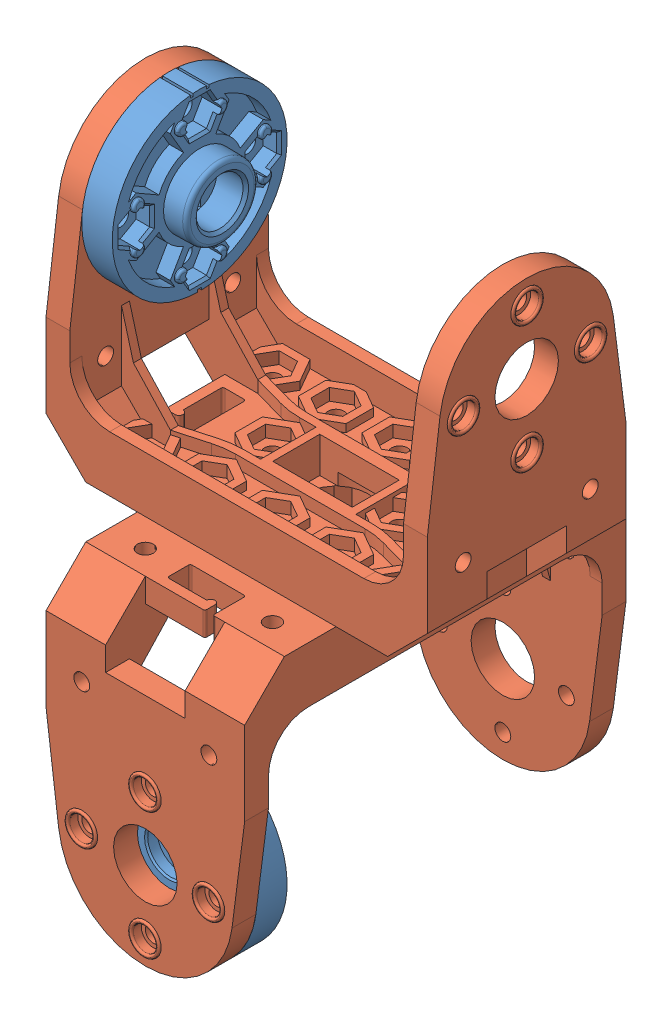
SolidWorks assembly Coxa_right, configuration Default. Lengths in mm.
Overall size (48.5 75 48.5).
4 component instances, 2 part files, 12 mates.
Components (placement in the parent):
- ServoHorn-2: ServoHorn [Default] at (0 0 -14.17) size (22 22 6.71)
- F2-1: F2 [Default] at (0 0 -14.3) x (1 0 0) z (0 0 -1) size (25 37.5 48.5)
- F2-2: F2 [Default] at (-0.0003 53 -14.2997) x (0 0 1) z (-1 0 0) size (25 37.5 48.5)
- ServoHorn-1: ServoHorn [Default] at (-0.1303 53 -14.2997) x (0 0 -1) z (-1 0 0) size (22 22 6.71)
Mates (geometry in assembly coordinates):
- Concentric11: concentric: cone of ? through (0 0 2.86) axis (0 0 -1)
- Coincident9: coincident: plane of ? through (4.1735 4.1691 0) normal (0 0 -1)
- Concentric4: concentric anti-aligned: cylinder of F2-1 through (-7.9997 -16.5 -6.3) axis (0 -1 0) radius 1; cylinder of F2-2 through (-7.9997 -36.5 -6.3) axis (0 1 0) radius 1
- Concentric5: concentric anti-aligned: cylinder of F2-1 through (8.0003 -16.5 -6.3) axis (0 -1 0) radius 1; cylinder of F2-2 through (8.0003 -36.5 -6.3) axis (0 1 0) radius 1
- Coincident5: coincident anti-aligned: plane of F2-1 through (12.5 -26.5 -38.3) normal (0 -1 0); plane of F2-2 through (24.0003 -26.5 -26.7997) normal (0 1 0)
- Concentric6: concentric anti-aligned: cylinder of ServoHorn-1 through (19.1603 -45 -14.2997) axis (1 0 0) radius 1.05; cylinder of F2-2 through (24.0003 -45 -14.2997) axis (-1 0 0) radius 1
- Concentric7: concentric anti-aligned: cylinder of ServoHorn-1 through (19.1603 -53 -6.2997) axis (1 0 0) radius 1.05; cylinder of F2-2 through (24.0003 -53 -6.2997) axis (-1 0 0) radius 1
- Coincident6: coincident anti-aligned: plane of F2-2 through (21.0003 -64.1221 -31.7861) normal (-1 0 0); plane of ServoHorn-1 through (21.0003 -41.5628 -2.8569) normal (1 0 0)
- Concentric9: concentric aligned: cylinder of F2-1 through (-8 0 -38.3) axis (0 0 1) radius 1; cylinder of ServoHorn-2 through (-8 0 4.86) axis (0 0 1) radius 1.05
- Concentric10: concentric aligned: cylinder of F2-1 through (8 0 -38.3) axis (0 0 1) radius 1; cylinder of ServoHorn-2 through (8 0 4.86) axis (0 0 1) radius 1.05
- Coincident7: coincident anti-aligned: plane of F2-1 through (17.4864 11.1221 6.7) normal (0 0 -1); plane of ServoHorn-2 through (11.4428 -11.4372 6.7) normal (0 0 1)
- Coincident10: coincident aligned: plane of ServoHorn-2 through (0 0 -14.17) normal (0 1 0); plane of assembly
